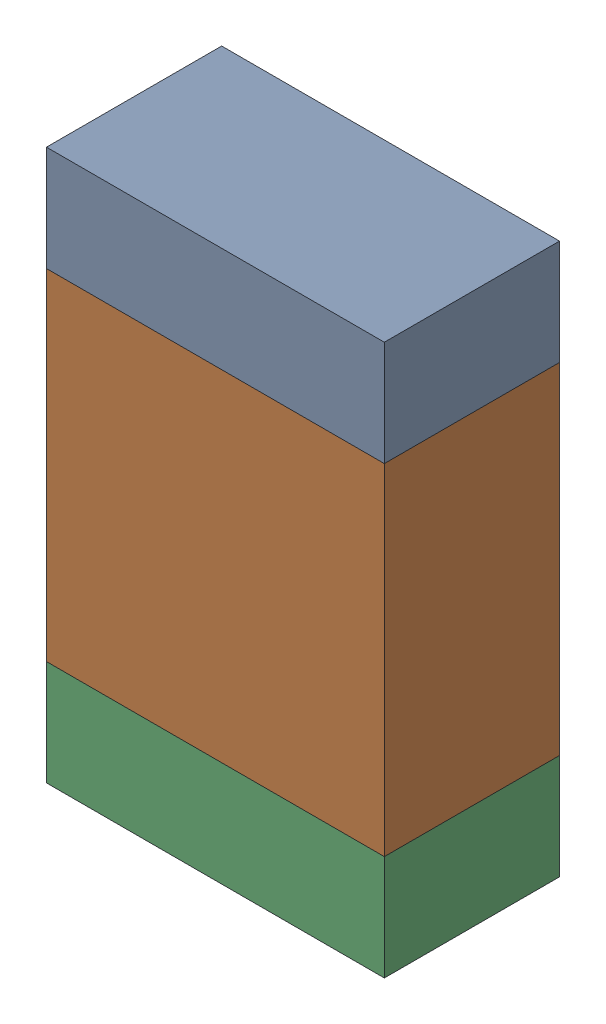
SolidWorks assembly R12-2, configuration Default. Lengths in mm.
Overall size (1.35 2.2 0.7).
6 component instances, 2 part files, 0 mates.
Components (placement in the parent):
- 959207304-2-1: 959207304-2 [Default] at (152.7811 87.2879 0) size (1.35 0.42 0.7)
  - Extruded-70-1: Extruded-70 [Default] at origin size (1.35 0.42 0.7)
- 959207440-2-1: 959207440-2 [Default] at (152.7811 86.3979 0) size (1.35 1.36 0.7)
  - Extruded-71-1: Extruded-71 [Default] at origin size (1.35 1.36 0.7)
- 959207304-2-2: 959207304-2 [Default] at (152.7811 85.5079 0) size (1.35 0.42 0.7)
  - Extruded-70-1: Extruded-70 [Default] at origin size (1.35 0.42 0.7)
